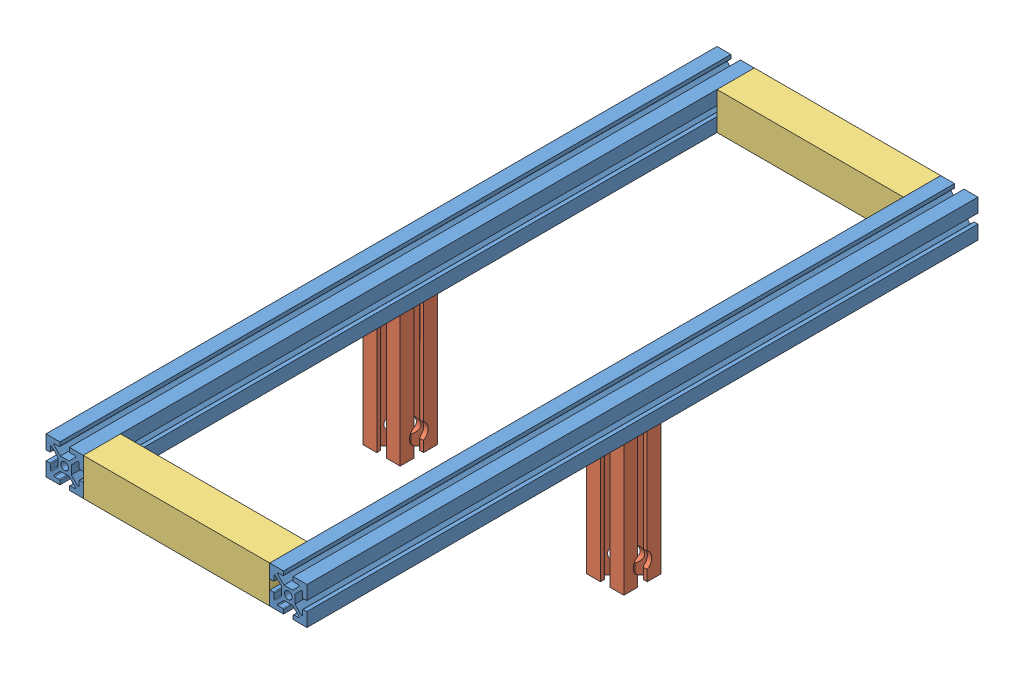
SolidWorks assembly frame, configuration Default. Lengths in mm.
Overall size (177.8 114.3 457.2).
6 component instances, 3 part files, 15 mates.
Components (placement in the parent):
- 8020-2ft-1: 8020-2ft [Default] at origin size (25.4 25.4 457.2)
- 8020-2ft-2: 8020-2ft [Default] at (-152.4 0 0) size (25.4 25.4 457.2)
- 8020-wheel_support-1: 8020-wheel_support [Default] at (0 -101.6 228.6) size (25.4 88.9 25.4)
- 8020-wheel_support-2: 8020-wheel_support [Default] at (-152.4 -101.6 228.6) size (25.4 88.9 25.4)
- 8020-cross_support-1: 8020-cross_support [Default] at (-139.7 0 12.7) size (127 25.4 25.4)
- 8020-cross_support-2: 8020-cross_support [Default] at (-139.7 0 444.5) size (127 25.4 25.4)
Mates (geometry in assembly coordinates):
- Coincident1: coincident aligned: plane of 8020-2ft-1 through (-12.7 12.7 457.2) normal (0 1 0); plane of 8020-2ft-2 through (-165.1 12.7 457.2) normal (0 1 0)
- Coincident2: coincident aligned: plane of 8020-2ft-1 through (12.7 12.7 457.2) normal (0 0 1); plane of 8020-2ft-2 through (-139.7 12.7 457.2) normal (0 0 1)
- Coincident42: coincident: plane of 8020-2ft-1 through (-12.7 -12.7 457.2) normal (0 -1 0); plane of 8020-wheel_support-1 through (12.7 -12.7 233.3307) normal (0 1 0)
- Coincident43: coincident: plane of 8020-2ft-1 through (12.7 -12.7 457.2) normal (1 0 0); plane of 8020-wheel_support-1 through (12.7 -12.7 207.9307) normal (1 0 0)
- Coincident53: coincident anti-aligned: plane of 8020-2ft-1 through (-12.7 -12.7 457.2) normal (-1 0 0); plane of 8020-cross_support-2 through (-12.7 12.7 431.8) normal (1 0 0)
- Coincident45: coincident anti-aligned: plane of 8020-2ft-2 through (-165.1 -12.7 457.2) normal (0 -1 0); plane of 8020-wheel_support-2 through (-139.7 -12.7 241.3) normal (0 1 0)
- Coincident46: coincident aligned: plane of 8020-2ft-2 through (-165.1 -12.7 457.2) normal (-1 0 0); plane of 8020-wheel_support-2 through (-165.1 -12.7 215.9) normal (-1 0 0)
- Coincident48: coincident anti-aligned: plane of 8020-2ft-2 through (-139.7 -12.7 457.2) normal (1 0 0); plane of 8020-cross_support-1 through (-139.7 12.7 0) normal (-1 0 0)
- Coincident49: coincident aligned: plane of 8020-2ft-2 through (-165.1 12.7 457.2) normal (0 1 0); plane of 8020-cross_support-1 through (-12.7 12.7 25.4) normal (0 1 0)
- Coincident50: coincident aligned: plane of 8020-2ft-2 through (-139.7 12.7 0) normal (0 0 -1); plane of 8020-cross_support-1 through (-12.7 -12.7 0) normal (0 0 -1)
- Coincident51: coincident anti-aligned: plane of 8020-2ft-2 through (-139.7 -12.7 457.2) normal (1 0 0); plane of 8020-cross_support-2 through (-139.7 12.7 431.8) normal (-1 0 0)
- Coincident52: coincident aligned: plane of 8020-2ft-2 through (-165.1 12.7 457.2) normal (0 1 0); plane of 8020-cross_support-2 through (-12.7 12.7 457.2) normal (0 1 0)
- Coincident54: coincident aligned: plane of 8020-2ft-2 through (-139.7 12.7 457.2) normal (0 0 1); plane of 8020-cross_support-2 through (-12.7 -12.7 457.2) normal (0 0 1)
- Distance1: distance = 215.9 mm: line of 8020-2ft-2 through (-165.1 -12.7 0) axis (1 0 0); line of 8020-wheel_support-2 through (-155.6385 -12.7 215.9) axis (-1 0 0)
- Distance2: distance = 215.9 mm: line of 8020-wheel_support-1 through (-3.2385 -12.7 215.9) axis (-1 0 0); line of 8020-2ft-1 through (-12.7 -12.7 0) axis (1 0 0)
